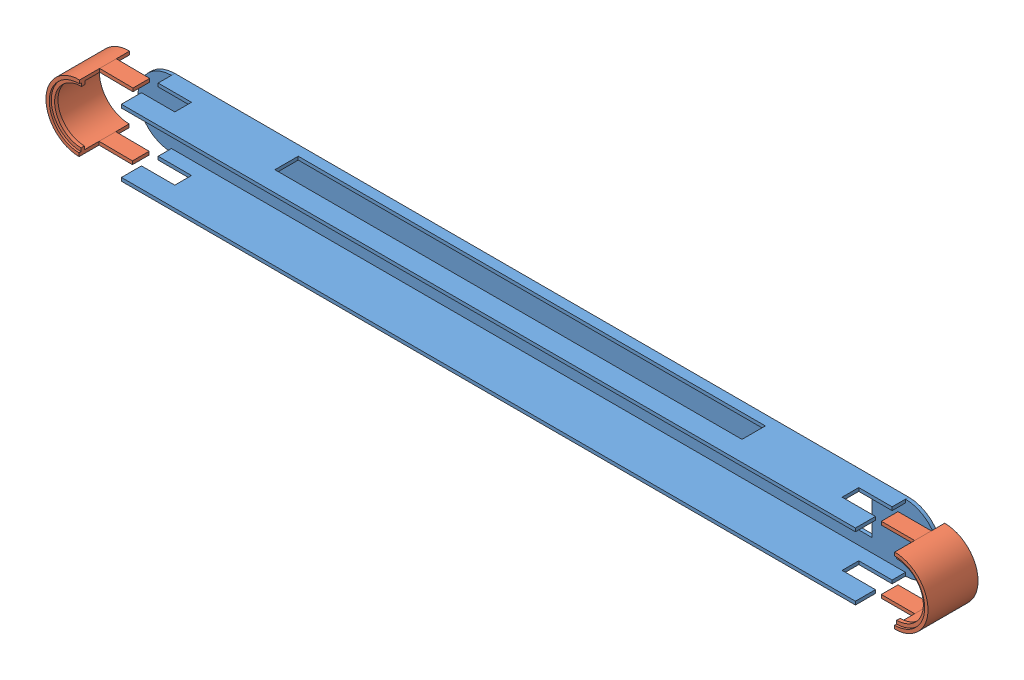
SolidWorks assembly Assem3, configuration Default. Lengths in mm.
Overall size (1323.62 101.1 80.99).
3 component instances, 2 part files, 0 mates.
Components (placement in the parent):
- joint-1: joint [Default] at (428.3746 641.7008 920.907) size (1200 100 80)
- joint-sides-1: joint-sides [Default] at (488.1427 640.8526 921.9012) size (100 100 75)
- joint-sides-2: joint-sides [Default] at (459.4636 636.308 920.5817) x (-0.999962 0.008727 0) z (0 0 1) size (100 100 75)
